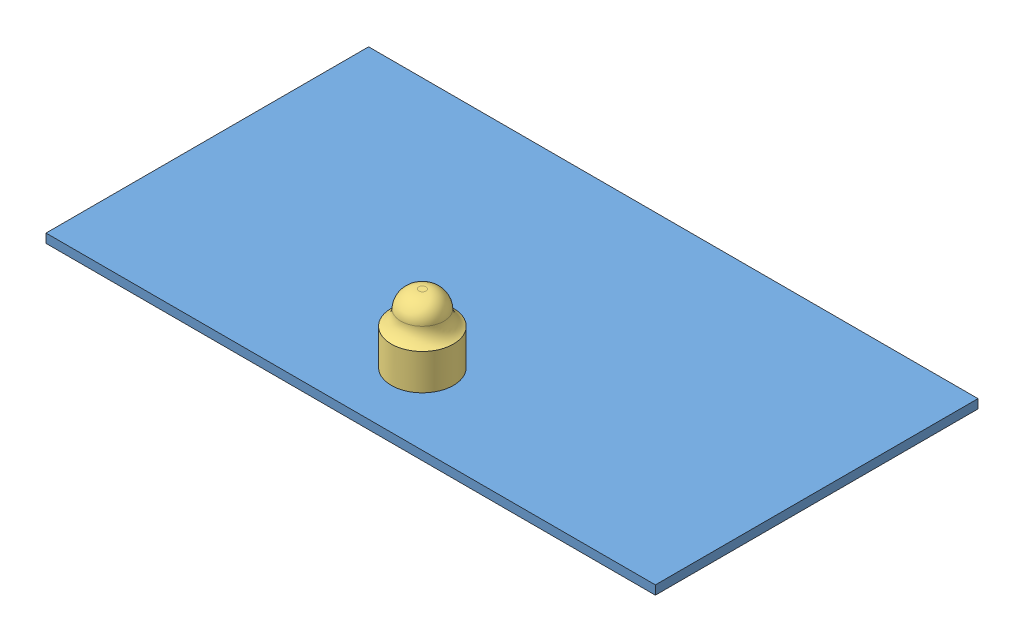
SolidWorks assembly Signal light board, configuration Default. Lengths in mm.
Overall size (431.8 79.12 228.6).
8 component instances, 3 part files, 18 mates.
Components (placement in the parent):
- Signal light board-1: Signal light board [Default] at (-162.3045 255.9691 481.3304) size (431.8 6.35 228.6)
- Speed Controller-1: Speed Controller [Default] at (220.9955 247.4243 339.4748) x (1 0 0) z (0 -1 0) size (30.12 70.11 24.39)
- Speed Controller-2: Speed Controller [Default] at (165.1155 247.4243 339.4748) x (1 0 0) z (0 -1 0) size (30.12 70.11 24.39)
- Speed Controller-3: Speed Controller [Default] at (-38.0845 247.4243 341.7098) x (1 0 0) z (0 -1 0) size (30.12 70.11 24.39)
- Speed Controller-4: Speed Controller [Default] at (-100.8284 247.4243 338.9376) x (1 0 0) z (0 -1 0) size (30.12 70.11 24.39)
- Speed Controller-5: Speed Controller [Default] at (114.3155 247.4243 339.4748) x (1 0 0) z (0 -1 0) size (30.12 70.11 24.39)
- Speed Controller-6: Speed Controller [Default] at (43.5955 247.4243 339.4748) x (1 0 0) z (0 -1 0) size (30.12 70.11 24.39)
- signal light-1: signal light [Default] at (53.5955 287.7191 430.5304) x (0.237335 0 0.971428) z (0.971428 0 -0.237335) size (43.94 79.12 43.94)
Mates (geometry in assembly coordinates):
- Coincident1: coincident anti-aligned: plane of Signal light board-1 through (-162.3045 255.9691 481.3304) normal (0 -1 0); plane of Speed Controller-1 through (235.9514 255.9691 304.5498) normal (0 1 0)
- Distance2: distance = 50.8 mm aligned: plane of Speed Controller-1 through (218.6955 254.0743 351.6954) normal (1 0 0); plane of Signal light board-1 through (269.4955 262.3191 481.3304) normal (1 0 0)
- Coincident4: coincident anti-aligned: plane of Signal light board-1 through (-162.3045 255.9691 481.3304) normal (0 -1 0); plane of Speed Controller-2 through (180.0714 255.9691 304.5498) normal (0 1 0)
- Distance4: distance = 101.6 mm aligned: plane of Speed Controller-2 through (167.8955 254.0743 352.9654) normal (1 0 0); plane of Signal light board-1 through (269.4955 262.3191 481.3304) normal (1 0 0)
- Coincident7: coincident anti-aligned: plane of Signal light board-1 through (-162.3045 255.9691 481.3304) normal (0 -1 0); plane of Speed Controller-3 through (-23.1286 255.9691 306.7848) normal (0 1 0)
- Distance5: distance = 304.8 mm aligned: plane of Speed Controller-3 through (-35.3045 254.0743 353.9304) normal (1 0 0); plane of Signal light board-1 through (269.4955 262.3191 481.3304) normal (1 0 0)
- Distance6: distance = 101.6 mm: plane of Speed Controller-3 through (-40.3845 254.0743 354.3304) normal (0 0 1); line of Signal light board-1 through (269.4955 262.3191 252.7304) axis (-1 0 0)
- Coincident14: coincident anti-aligned: plane of Signal light board-1 through (-162.3045 255.9691 481.3304) normal (0 -1 0); plane of Speed Controller-4 through (-85.8724 255.9691 304.0126) normal (0 1 0)
- Coincident15: coincident anti-aligned: plane of Signal light board-1 through (-162.3045 255.9691 481.3304) normal (0 -1 0); plane of Speed Controller-5 through (129.2714 255.9691 304.5498) normal (0 1 0)
- Distance9: distance = 152.4 mm aligned: plane of Speed Controller-5 through (117.0955 254.0743 352.9654) normal (1 0 0); plane of Signal light board-1 through (269.4955 262.3191 481.3304) normal (1 0 0)
- Distance10: distance = 101.6 mm aligned: plane of Speed Controller-5 through (113.1555 251.6743 354.3304) normal (0 0 -1); plane of Signal light board-1 through (-162.3045 262.3191 252.7304) normal (0 0 -1)
- Distance11: distance = 101.6 mm aligned: plane of Signal light board-1 through (-162.3045 262.3191 252.7304) normal (0 0 -1); plane of Speed Controller-2 through (163.9555 251.6743 354.3304) normal (0 0 -1)
- Distance12: distance = 101.6 mm: line of Signal light board-1 through (269.4955 262.3191 252.7304) axis (-1 0 0); plane of Speed Controller-1 through (219.8355 251.6743 354.3304) normal (0 0 -1)
- Coincident21: coincident anti-aligned: plane of Signal light board-1 through (-162.3045 255.9691 481.3304) normal (0 -1 0); plane of Speed Controller-6 through (58.5514 255.9691 304.5498) normal (0 1 0)
- Distance13: distance = 203.2 mm aligned: plane of Speed Controller-6 through (40.8955 254.0743 353.3654) normal (-1 0 0); plane of Signal light board-1 through (-162.3045 262.3191 481.3304) normal (-1 0 0)
- Distance14: distance = 101.6 mm aligned: plane of Speed Controller-6 through (42.4355 251.6743 354.3304) normal (0 0 -1); plane of Signal light board-1 through (-162.3045 262.3191 252.7304) normal (0 0 -1)
- Concentric1: concentric aligned: cylinder of Signal light board-1 through (53.5955 255.9691 430.5304) axis (0 1 0) radius 14.224; cylinder of signal light-1 through (53.5955 254.3181 430.5304) axis (0 1 0) radius 14.224
- Coincident25: coincident anti-aligned: plane of Signal light board-1 through (-162.3045 262.3191 481.3304) normal (0 1 0); plane of signal light-1 through (53.5955 262.3191 430.5304) normal (0 -1 0)
